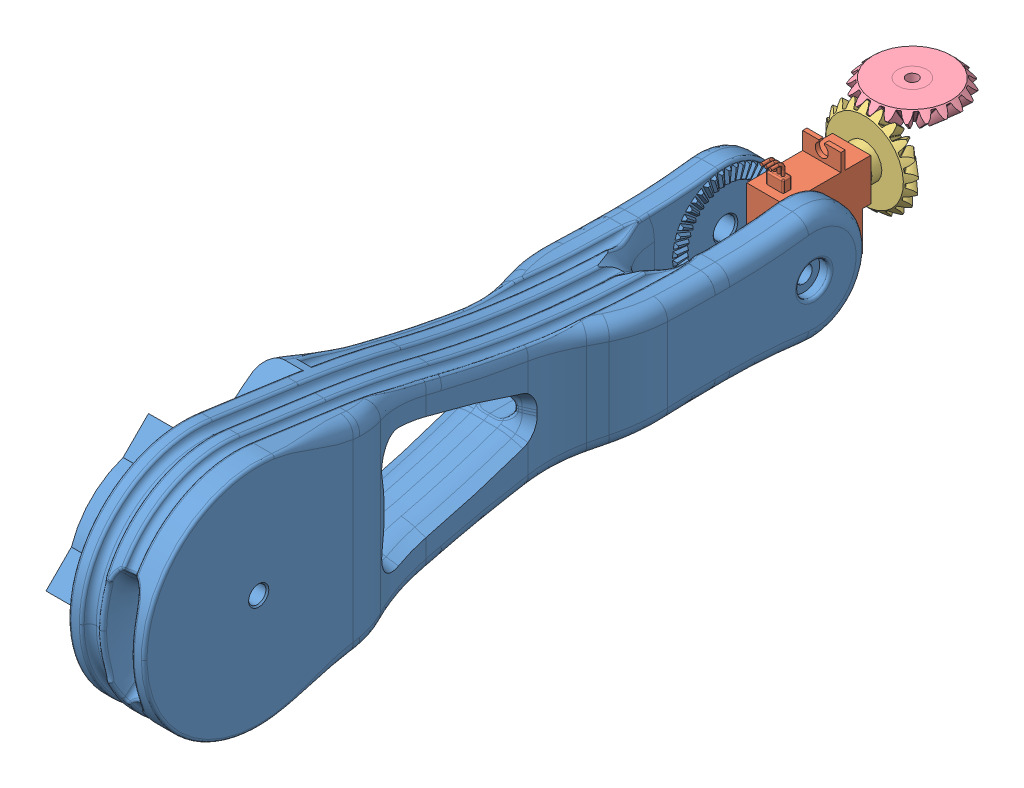
SolidWorks assembly Grabber, configuration Domyślna. Lengths in mm.
Overall size (70.01 82.39 311.27).
4 component instances, 4 part files, 13 mates.
Components (placement in the parent):
- 5 Arm2-1: 5 Arm2 [Domyślna] at (0 0 190) size (70.01 82.39 258.96)
- servo HD-1160A-1: servo HD-1160A [Domyślna] at (0 6.4003 -3.9) x (0 1 0) z (-1 0 0) size (42.5 33.6 13.2)
- straight bevel gear_iso-1: straight bevel gear_iso [ISO - Straight bevel gear 1.5M 20GT 20PT 20PA 10FW ---20O12H20MD5.0N] at (0 6.4003 -37.9241) x (0 0 -1) z (0.063888 0.997957 0) size (13.05 32.01 32.01)
- straight bevel pinion_iso-1: straight bevel pinion_iso [ISO - Straight bevel pinion 1.5M20PT 20GT 20PA 10FW ---20O10H5MD4.0N] at (0 22.9003 -54.4241) x (0 -1 0) z (0.088099 0 -0.996112) size (9.63 32.01 32.01)
Mates (geometry in assembly coordinates):
- Wspólnie1: coincident aligned: plane of 5 Arm2-1 through (0 0 190) normal (1 0 0); plane of assembly through (0 0 0) normal (1 0 0)
- Wspólnie2: coincident: line of 5 Arm2-1 through (94.1994 -49.8552 0) axis (0 1 0); plane of assembly
- Wspólnie3: coincident aligned: plane of 5 Arm2-1 through (0 0 190) normal (0 1 0); plane of assembly through (0 0 0) normal (0 1 0)
- Równolegle1: parallel aligned: plane of servo HD-1160A-1 through (0 6.4003 -3.9) normal (0 1 0); plane of assembly through (0 0 0) normal (0 1 0)
- Wspólnie5: coincident anti-aligned: plane of servo HD-1160A-1 through (0 6.4003 -3.9) normal (-1 0 0); plane of assembly through (0 0 0) normal (1 0 0)
- Odległość4: distance = 3 mm anti-aligned: plane of servo HD-1160A-1 through (0 6.4003 -37.5) normal (0 0 -1); plane of straight bevel gear_iso-1 through (0 6.4003 -34.5) normal (0 0 1)
- Wspólnie7: coincident: line of straight bevel pinion_iso-1 through (0 15.0863 -54.4241) axis (0 1 0); plane of assembly
- Odległość2: distance = 16.5 mm: line of straight bevel pinion_iso-1 through (0 15.0863 -54.4241) axis (0 1 0); plane of straight bevel gear_iso-1 through (0 6.4003 -37.9241) normal (0 0 1)
- Odległość3: distance = 16.5 mm: line of straight bevel gear_iso-1 through (0 6.4003 -45.7381) axis (0 0 1); plane of straight bevel pinion_iso-1 through (0 22.9003 -54.4241) normal (0 1 0)
- Wspólnie10: coincident: line of straight bevel gear_iso-1 through (0 6.4003 -45.7381) axis (0 0 1); plane of assembly
- Wspólnie12: coincident aligned: line of servo HD-1160A-1 through (0 6.4003 -51.0716) axis (0 0 1); line of straight bevel gear_iso-1 through (0 6.4003 -45.7381) axis (0 0 1)
- Wiązanie kół zębatych1: gear = 20 : 20 mm: circle of straight bevel pinion_iso-1; circle of straight bevel gear_iso-1
- Odległość5: distance = 1 mm anti-aligned: plane of servo HD-1160A-1 through (0 6.4003 -3.9) normal (0 0 1); cylinder of 5 Arm2-1 through (-20.625 0 0) axis (1 0 0) radius 2.9
